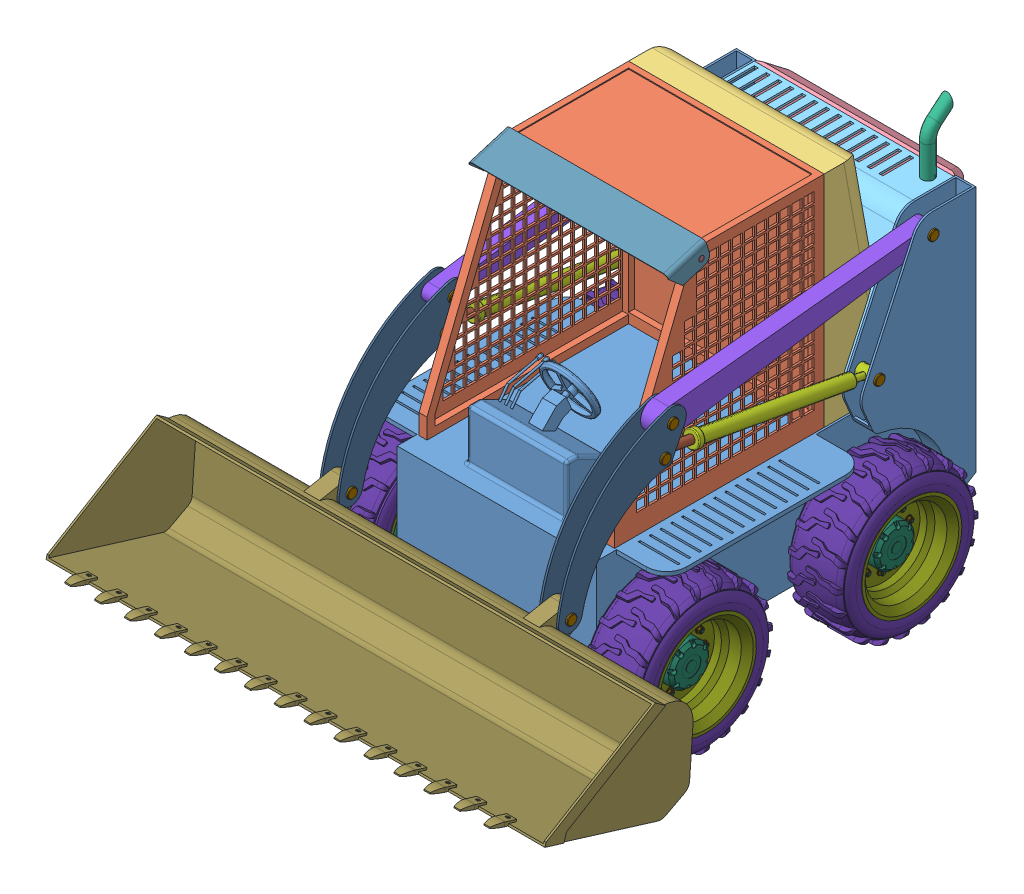
SolidWorks assembly Main Assembly, configuration Default. Lengths in mm.
Overall size (2500 2109.45 3011.96).
86 component instances, 18 part files, 55 mates.
Components (placement in the parent):
- 1. Main Body-1: 1. Main Body [Default] at origin size (1500 1375 1800)
- 2. Cabin-1: 2. Cabin [Default] at (0 600 240) size (980 1100 1050)
- 11. Back Support-1: 11. Back Support [Default] at (0 1150 -285) x (0 0 -1) z (1 0 0) size (350 1100 980)
- 4. Back cover with light-1: 4. Back cover with light [Default] at (0 987.5 -1025) size (1000 775 130)
- 10. Back Cover-1: 10. Back Cover [Default] at (0 1375 -925) x (0 0 -1) z (1 0 0) size (539.33 589.21 1000)
- 12. Exhaust Pipe-1: 12. Exhaust Pipe [Default] at (435 1671.4181 -974.9067) size (60 319.4 125.62)
- 6. Cylinder Body-1: 6. Cylinder Body [Default] at (550 942.7605 442.5974) x (-1 0 0) z (0 0.177626 0.984098) size (85 85 935)
- 9. Lifting Arm 2-1: 9. Lifting Arm 2 [Default] at (550 1275 -719.0464) x (0 0.125982 -0.992033) z (1 0 0) size (1425 140 80)
- 13. Arm pin-1: 13. Arm pin [Default] at (610 1275 -719.0464) x (1 0 0) z (0 -0.292261 0.956339) size (120 50 50)
- 13. Arm pin-2: 13. Arm pin [Default] at (610 782.0093 -448.0114) size (120 50 50)
- 8. Lifting arm 1-1: 8. Lifting arm 1 [Default] at (595 1109.3336 585.4763) x (0 0.085474 -0.99634) z (1 0 0) size (690 680 10)
- 7.Cylinder Rod-1: 7.Cylinder Rod [Default] at (550 975.5356 624.1817) x (0 -0.177626 -0.984098) z (1 0 0) size (950 60 80)
- 8. Lifting arm 1-2: 8. Lifting arm 1 [Default] at (505 1109.3336 585.4763) x (0 0.085474 -0.99634) z (1 0 0) size (690 680 10)
- 13. Arm pin-4: 13. Arm pin [Default] at (490 975.5356 624.1817) x (-1 0 0) z (0 0.679336 -0.733827) size (120 50 50)
- 13. Arm pin-5: 13. Arm pin [Default] at (610 1109.3336 585.4763) x (1 0 0) z (0 -0.694207 -0.719775) size (120 50 50)
- 9. Lifting Arm 2-2: 9. Lifting Arm 2 [Default] at (-550 1105.5541 615.2373) x (0 -0.125982 0.992033) z (-1 0 0) size (1425 140 80)
- 13. Arm pin-6: 13. Arm pin [Default] at (-610 1109.3336 585.4763) x (-1 0 0) z (0 0.694207 0.719775) size (120 50 50)
- 13. Arm pin-7: 13. Arm pin [Default] at (-490 975.5356 624.1817) x (1 0 0) z (0 -0.679336 0.733827) size (120 50 50)
- 8. Lifting arm 1-3: 8. Lifting arm 1 [Default] at (-595 1109.3336 585.4763) x (0 0.085474 -0.99634) z (1 0 0) size (690 680 10)
- 8. Lifting arm 1-4: 8. Lifting arm 1 [Default] at (-505 1109.3336 585.4763) x (0 0.085474 -0.99634) z (1 0 0) size (690 680 10)
- 7.Cylinder Rod-2: 7.Cylinder Rod [Default] at (-550 975.5356 624.1817) x (0 -0.177626 -0.984098) z (1 0 0) size (950 60 80)
- 6. Cylinder Body-2: 6. Cylinder Body [Default] at (-550 942.7605 442.5974) x (1 0 0) z (0 0.177626 0.984098) size (85 85 935)
- 13. Arm pin-8: 13. Arm pin [Default] at (-610 1275 -719.0464) x (-1 0 0) z (0 0.292261 -0.956339) size (120 50 50)
- 13. Arm pin-9: 13. Arm pin [Default] at (-610 782.0093 -448.0114) x (-1 0 0) z (0 0 -1) size (120 50 50)
- 3. Bucket-1: 3. Bucket [Default] at (0 149.3103 1587.7184) x (1 0 0) z (0 0.293221 0.956045) size (2500 554.94 810.74)
- 13. Arm pin-10: 13. Arm pin [Default] at (-490 513.4808 1096.4161) x (1 0 0) z (0 -0.694207 -0.719775) size (120 50 50)
- 13. Arm pin-11: 13. Arm pin [Default] at (610 513.4808 1096.4161) x (1 0 0) z (0 -0.688251 -0.725473) size (120 50 50)
- 14. Cabin pin-1: 14. Cabin pin [Default] at (-484 1650 340) x (-1 0 0) z (0 -0.924225 -0.381849) size (20 26 26)
- 5. Cabin Cap-1: 5. Cabin Cap [Default] at (0 1594.3596 385.871) x (1 0 0) z (0 -0.289151 0.957284) size (1000 100 200)
- 14. Cabin pin-2: 14. Cabin pin [Default] at (484 1650 340) size (20 26 26)
- Tire Sub Assembly-1: Tire Sub Assembly [Default] at (194.4921 299.2826 729.3509) x (1 0 0) z (0 -0.820784 -0.571238) size (367.75 833.89 833.89)
  - 15. Axle-1: 15. Axle [Default] at (370.5079 7.8342 176.4257) size (290 300 300)
  - 16. Rim-1: 16. Rim [Default] at (475.5079 7.8342 176.4257) size (300 500 500)
  - 17. Tire-1: 17. Tire [Default] at (475.5079 7.8342 176.4257) x (1 0 0) z (0 0.148505 0.988912) size (305.49 733.15 733.15)
  - hex flange nut_am-1: hex flange nut_am [B18.2.2.4M - Hex flange nut, M16 x 2 --N] at (496.5079 113.0064 100.0136) x (0 0 -1) z (1 0 0) size (34.5 34.5 16)
  - hex flange nut_am-2: hex flange nut_am [B18.2.2.4M - Hex flange nut, M16 x 2 --N] at (496.5079 137.8342 176.4257) x (0 0 -1) z (1 0 0) size (34.5 34.5 16)
  - hex flange nut_am-3: hex flange nut_am [B18.2.2.4M - Hex flange nut, M16 x 2 --N] at (496.5079 113.0064 252.8378) x (0 0 -1) z (1 0 0) size (34.5 34.5 16)
  - hex flange nut_am-4: hex flange nut_am [B18.2.2.4M - Hex flange nut, M16 x 2 --N] at (496.5079 48.0064 300.063) x (0 0 -1) z (1 0 0) size (34.5 34.5 16)
  - hex flange nut_am-5: hex flange nut_am [B18.2.2.4M - Hex flange nut, M16 x 2 --N] at (496.5079 -32.338 300.063) x (0 0 -1) z (1 0 0) size (34.5 34.5 16)
  - hex flange nut_am-6: hex flange nut_am [B18.2.2.4M - Hex flange nut, M16 x 2 --N] at (496.5079 -97.338 252.8378) x (0 0 -1) z (1 0 0) size (34.5 34.5 16)
  - hex flange nut_am-7: hex flange nut_am [B18.2.2.4M - Hex flange nut, M16 x 2 --N] at (496.5079 -122.1658 176.4257) x (0 0 -1) z (1 0 0) size (34.5 34.5 16)
  - hex flange nut_am-8: hex flange nut_am [B18.2.2.4M - Hex flange nut, M16 x 2 --N] at (496.5079 -97.338 100.0136) x (0 0 -1) z (1 0 0) size (34.5 34.5 16)
  - hex flange nut_am-9: hex flange nut_am [B18.2.2.4M - Hex flange nut, M16 x 2 --N] at (496.5079 -32.338 52.7883) x (0 0 -1) z (1 0 0) size (34.5 34.5 16)
  - hex flange nut_am-10: hex flange nut_am [B18.2.2.4M - Hex flange nut, M16 x 2 --N] at (496.5079 48.0064 52.7883) x (0 0 -1) z (1 0 0) size (34.5 34.5 16)
- Tire Sub Assembly-2: Tire Sub Assembly [Default] at (194.4921 123.7634 -569.6397) x (1 0 0) z (0 0.10455 0.99452) size (367.75 833.89 833.89)
  - 15. Axle-1: 15. Axle [Default] at (370.5079 7.8342 176.4257) size (290 300 300)
  - 16. Rim-1: 16. Rim [Default] at (475.5079 7.8342 176.4257) size (300 500 500)
  - 17. Tire-1: 17. Tire [Default] at (475.5079 7.8342 176.4257) x (1 0 0) z (0 0.148505 0.988912) size (305.49 733.15 733.15)
  - hex flange nut_am-1: hex flange nut_am [B18.2.2.4M - Hex flange nut, M16 x 2 --N] at (496.5079 113.0064 100.0136) x (0 0 -1) z (1 0 0) size (34.5 34.5 16)
  - hex flange nut_am-2: hex flange nut_am [B18.2.2.4M - Hex flange nut, M16 x 2 --N] at (496.5079 137.8342 176.4257) x (0 0 -1) z (1 0 0) size (34.5 34.5 16)
  - hex flange nut_am-3: hex flange nut_am [B18.2.2.4M - Hex flange nut, M16 x 2 --N] at (496.5079 113.0064 252.8378) x (0 0 -1) z (1 0 0) size (34.5 34.5 16)
  - hex flange nut_am-4: hex flange nut_am [B18.2.2.4M - Hex flange nut, M16 x 2 --N] at (496.5079 48.0064 300.063) x (0 0 -1) z (1 0 0) size (34.5 34.5 16)
  - hex flange nut_am-5: hex flange nut_am [B18.2.2.4M - Hex flange nut, M16 x 2 --N] at (496.5079 -32.338 300.063) x (0 0 -1) z (1 0 0) size (34.5 34.5 16)
  - hex flange nut_am-6: hex flange nut_am [B18.2.2.4M - Hex flange nut, M16 x 2 --N] at (496.5079 -97.338 252.8378) x (0 0 -1) z (1 0 0) size (34.5 34.5 16)
  - hex flange nut_am-7: hex flange nut_am [B18.2.2.4M - Hex flange nut, M16 x 2 --N] at (496.5079 -122.1658 176.4257) x (0 0 -1) z (1 0 0) size (34.5 34.5 16)
  - hex flange nut_am-8: hex flange nut_am [B18.2.2.4M - Hex flange nut, M16 x 2 --N] at (496.5079 -97.338 100.0136) x (0 0 -1) z (1 0 0) size (34.5 34.5 16)
  - hex flange nut_am-9: hex flange nut_am [B18.2.2.4M - Hex flange nut, M16 x 2 --N] at (496.5079 -32.338 52.7883) x (0 0 -1) z (1 0 0) size (34.5 34.5 16)
  - hex flange nut_am-10: hex flange nut_am [B18.2.2.4M - Hex flange nut, M16 x 2 --N] at (496.5079 48.0064 52.7883) x (0 0 -1) z (1 0 0) size (34.5 34.5 16)
- Tire Sub Assembly-3: Tire Sub Assembly [Default] at (-194.4921 282.0158 752.2997) x (-1 0 0) z (0 -0.776273 -0.630397) size (367.75 833.89 833.89)
  - 15. Axle-1: 15. Axle [Default] at (370.5079 7.8342 176.4257) size (290 300 300)
  - 16. Rim-1: 16. Rim [Default] at (475.5079 7.8342 176.4257) size (300 500 500)
  - 17. Tire-1: 17. Tire [Default] at (475.5079 7.8342 176.4257) x (1 0 0) z (0 0.148505 0.988912) size (305.49 733.15 733.15)
  - hex flange nut_am-1: hex flange nut_am [B18.2.2.4M - Hex flange nut, M16 x 2 --N] at (496.5079 113.0064 100.0136) x (0 0 -1) z (1 0 0) size (34.5 34.5 16)
  - hex flange nut_am-2: hex flange nut_am [B18.2.2.4M - Hex flange nut, M16 x 2 --N] at (496.5079 137.8342 176.4257) x (0 0 -1) z (1 0 0) size (34.5 34.5 16)
  - hex flange nut_am-3: hex flange nut_am [B18.2.2.4M - Hex flange nut, M16 x 2 --N] at (496.5079 113.0064 252.8378) x (0 0 -1) z (1 0 0) size (34.5 34.5 16)
  - hex flange nut_am-4: hex flange nut_am [B18.2.2.4M - Hex flange nut, M16 x 2 --N] at (496.5079 48.0064 300.063) x (0 0 -1) z (1 0 0) size (34.5 34.5 16)
  - hex flange nut_am-5: hex flange nut_am [B18.2.2.4M - Hex flange nut, M16 x 2 --N] at (496.5079 -32.338 300.063) x (0 0 -1) z (1 0 0) size (34.5 34.5 16)
  - hex flange nut_am-6: hex flange nut_am [B18.2.2.4M - Hex flange nut, M16 x 2 --N] at (496.5079 -97.338 252.8378) x (0 0 -1) z (1 0 0) size (34.5 34.5 16)
  - hex flange nut_am-7: hex flange nut_am [B18.2.2.4M - Hex flange nut, M16 x 2 --N] at (496.5079 -122.1658 176.4257) x (0 0 -1) z (1 0 0) size (34.5 34.5 16)
  - hex flange nut_am-8: hex flange nut_am [B18.2.2.4M - Hex flange nut, M16 x 2 --N] at (496.5079 -97.338 100.0136) x (0 0 -1) z (1 0 0) size (34.5 34.5 16)
  - hex flange nut_am-9: hex flange nut_am [B18.2.2.4M - Hex flange nut, M16 x 2 --N] at (496.5079 -32.338 52.7883) x (0 0 -1) z (1 0 0) size (34.5 34.5 16)
  - hex flange nut_am-10: hex flange nut_am [B18.2.2.4M - Hex flange nut, M16 x 2 --N] at (496.5079 48.0064 52.7883) x (0 0 -1) z (1 0 0) size (34.5 34.5 16)
- Tire Sub Assembly-4: Tire Sub Assembly [Default] at (-194.4921 307.0923 -314.3192) x (-1 0 0) z (0 -0.908931 -0.416946) size (367.75 833.89 833.89)
  - 15. Axle-1: 15. Axle [Default] at (370.5079 7.8342 176.4257) size (290 300 300)
  - 16. Rim-1: 16. Rim [Default] at (475.5079 7.8342 176.4257) size (300 500 500)
  - 17. Tire-1: 17. Tire [Default] at (475.5079 7.8342 176.4257) x (1 0 0) z (0 0.148505 0.988912) size (305.49 733.15 733.15)
  - hex flange nut_am-1: hex flange nut_am [B18.2.2.4M - Hex flange nut, M16 x 2 --N] at (496.5079 113.0064 100.0136) x (0 0 -1) z (1 0 0) size (34.5 34.5 16)
  - hex flange nut_am-2: hex flange nut_am [B18.2.2.4M - Hex flange nut, M16 x 2 --N] at (496.5079 137.8342 176.4257) x (0 0 -1) z (1 0 0) size (34.5 34.5 16)
  - hex flange nut_am-3: hex flange nut_am [B18.2.2.4M - Hex flange nut, M16 x 2 --N] at (496.5079 113.0064 252.8378) x (0 0 -1) z (1 0 0) size (34.5 34.5 16)
  - hex flange nut_am-4: hex flange nut_am [B18.2.2.4M - Hex flange nut, M16 x 2 --N] at (496.5079 48.0064 300.063) x (0 0 -1) z (1 0 0) size (34.5 34.5 16)
  - hex flange nut_am-5: hex flange nut_am [B18.2.2.4M - Hex flange nut, M16 x 2 --N] at (496.5079 -32.338 300.063) x (0 0 -1) z (1 0 0) size (34.5 34.5 16)
  - hex flange nut_am-6: hex flange nut_am [B18.2.2.4M - Hex flange nut, M16 x 2 --N] at (496.5079 -97.338 252.8378) x (0 0 -1) z (1 0 0) size (34.5 34.5 16)
  - hex flange nut_am-7: hex flange nut_am [B18.2.2.4M - Hex flange nut, M16 x 2 --N] at (496.5079 -122.1658 176.4257) x (0 0 -1) z (1 0 0) size (34.5 34.5 16)
  - hex flange nut_am-8: hex flange nut_am [B18.2.2.4M - Hex flange nut, M16 x 2 --N] at (496.5079 -97.338 100.0136) x (0 0 -1) z (1 0 0) size (34.5 34.5 16)
  - hex flange nut_am-9: hex flange nut_am [B18.2.2.4M - Hex flange nut, M16 x 2 --N] at (496.5079 -32.338 52.7883) x (0 0 -1) z (1 0 0) size (34.5 34.5 16)
  - hex flange nut_am-10: hex flange nut_am [B18.2.2.4M - Hex flange nut, M16 x 2 --N] at (496.5079 48.0064 52.7883) x (0 0 -1) z (1 0 0) size (34.5 34.5 16)
Mates (geometry in assembly coordinates):
- Coincident1: coincident anti-aligned: plane of 1. Main Body-1 through (500 600 865) normal (0 1 0); plane of 2. Cabin-1 through (490 600 -285) normal (0 -1 0)
- Coincident3: coincident aligned: plane of 1. Main Body-1 through (500 580 765) normal (0 0 1); plane of 2. Cabin-1 through (490 600 765) normal (0 0 1)
- Width1: width anti-aligned: plane of 1. Main Body-1 through (500 0 0) normal (1 0 0); plane of 2. Cabin-1 through (-500 0 0) normal (-1 0 0); plane of 1. Main Body-1 through (-490 600 240) normal (-1 0 0); plane of 2. Cabin-1 through (490 600 240) normal (1 0 0)
- Coincident4: coincident anti-aligned: plane of 2. Cabin-1 through (490 1700 -285) normal (0 0 -1); plane of 15. Back Support-1 through (490 1700 -285) normal (0 0 1)
- Coincident5: coincident aligned: plane of 2. Cabin-1 through (490 1700 365) normal (0 1 0); plane of 15. Back Support-1 through (490 1700 -485) normal (0 1 0)
- Coincident6: coincident aligned: plane of 2. Cabin-1 through (490 600 240) normal (1 0 0); plane of 15. Back Support-1 through (490 1150 -285) normal (1 0 0)
- Coincident7: coincident aligned: plane of 1. Main Body-1 through (590 140.5963 -925) normal (0 0 1); plane of 4. Back cover with light-1 through (0 987.5 -925) normal (0 0 1)
- Coincident8: coincident aligned: plane of 1. Main Body-1 through (510 1375 -935) normal (0 1 0); plane of 4. Back cover with light-1 through (-500 1375 -925) normal (0 1 0)
- Coincident9: coincident anti-aligned: plane of 1. Main Body-1 through (500 81.3643 -809.3539) normal (-1 0 0); plane of 4. Back cover with light-1 through (500 1375 -925) normal (1 0 0)
- Coincident10: coincident aligned: plane of 1. Main Body-1 through (510 1375 -935) normal (0 1 0); plane of 14. Back Cove-1 through (500 1375 -925) normal (0 1 0)
- Coincident11: coincident anti-aligned: plane of 4. Back cover with light-1 through (0 987.5 -925) normal (0 0 1); plane of 14. Back Cove-1 through (500 1375 -925) normal (0 0 -1)
- Coincident12: coincident anti-aligned: plane of 1. Main Body-1 through (-500 81.3643 -809.3539) normal (1 0 0); plane of 14. Back Cove-1 through (-500 1275 -719.05) normal (-1 0 0)
- Concentric1: concentric anti-aligned: cylinder of 14. Back Cove-1 through (435 785.7865 -860) axis (0 1 0) radius 30; cylinder of 16. Exhaust Pipe-1 through (435 1533.0323 -860) axis (0 -1 0) radius 30
- Coincident13: coincident anti-aligned: plane of 14. Back Cove-1 through (500 1375 -925) normal (0 1 0); plane of 16. Exhaust Pipe-1 through (435 1375 -860) normal (0 -1 0)
- Parallel1: parallel aligned: plane of 1. Main Body-1 through (0 0 0) normal (1 0 0); plane of 16. Exhaust Pipe-1 through (435 1671.4181 -974.9067) normal (1 0 0)
- Concentric2: concentric anti-aligned: cylinder of 1. Main Body-1 through (-600 1275 -719.0464) axis (1 0 0) radius 20; cylinder of 13. Lifting Arm 2-1 through (590 1275 -719.0464) axis (-1 0 0) radius 20
- Coincident15: coincident anti-aligned: plane of 1. Main Body-1 through (510 81.3643 -809.3539) normal (1 0 0); plane of 13. Lifting Arm 2-1 through (510 1109.3336 585.4763) normal (-1 0 0)
- Concentric3: concentric aligned: cylinder of 1. Main Body-1 through (-600 782.0093 -448.0114) axis (1 0 0) radius 15; cylinder of 10. Cylinder Body-1 through (510 782.0093 -448.0114) axis (1 0 0) radius 15
- Coincident16: coincident anti-aligned: plane of 1. Main Body-1 through (510 81.3643 -809.3539) normal (1 0 0); plane of 10. Cylinder Body-1 through (510 782.0093 -448.0114) normal (-1 0 0)
- Concentric4: concentric aligned: cylinder of 1. Main Body-1 through (-600 1275 -719.0464) axis (1 0 0) radius 20; cylinder of 17. Arm pin-1 through (610 1275 -719.0464) axis (1 0 0) radius 15
- Coincident17: coincident anti-aligned: plane of 1. Main Body-1 through (600 81.3643 -809.3539) normal (1 0 0); plane of 17. Arm pin-1 through (600 1289.3451 -714.6625) normal (-1 0 0)
- Concentric5: concentric aligned: cylinder of 1. Main Body-1 through (-600 782.0093 -448.0114) axis (1 0 0) radius 15; cylinder of 17. Arm pin-2 through (610 782.0093 -448.0114) axis (1 0 0) radius 15
- Coincident18: coincident anti-aligned: plane of 1. Main Body-1 through (600 81.3643 -809.3539) normal (1 0 0); plane of 17. Arm pin-2 through (600 797.0093 -448.0114) normal (-1 0 0)
- Concentric7: concentric aligned: cylinder of 13. Lifting Arm 2-1 through (590 1109.3336 585.4763) axis (-1 0 0) radius 25; cylinder of 12. Lifting arm 1-1 through (600 1109.3336 585.4763) axis (-1 0 0) radius 20
- Coincident20: coincident anti-aligned: plane of 13. Lifting Arm 2-1 through (590 1109.3336 585.4763) normal (1 0 0); plane of 12. Lifting arm 1-1 through (590 1109.3336 585.4763) normal (-1 0 0)
- Concentric10: concentric aligned: cylinder of 10. Cylinder Body-1 through (550 798.8838 -354.5221) axis (0 0.177626 0.984098) radius 32.5; cylinder of 11.Cylinder Rod-1 through (550 812.1202 -281.1886) axis (0 0.177626 0.984098) radius 20
- Concentric11: concentric aligned: cylinder of 12. Lifting arm 1-1 through (600 975.5356 624.1817) axis (-1 0 0) radius 15; cylinder of 11.Cylinder Rod-1 through (590 975.5356 624.1817) axis (-1 0 0) radius 15
- Concentric12: concentric aligned: cylinder of 13. Lifting Arm 2-1 through (590 1109.3336 585.4763) axis (-1 0 0) radius 25; cylinder of 12. Lifting arm 1-2 through (510 1109.3336 585.4763) axis (-1 0 0) radius 20
- Concentric13: concentric aligned: cylinder of 11.Cylinder Rod-1 through (590 975.5356 624.1817) axis (-1 0 0) radius 15; cylinder of 12. Lifting arm 1-2 through (510 975.5356 624.1817) axis (-1 0 0) radius 15
- Coincident21: coincident anti-aligned: plane of 13. Lifting Arm 2-1 through (510 1109.3336 585.4763) normal (-1 0 0); plane of 12. Lifting arm 1-2 through (510 1109.3336 585.4763) normal (1 0 0)
- Concentric20: concentric aligned: cylinder of 11.Cylinder Rod-1 through (590 975.5356 624.1817) axis (-1 0 0) radius 15; cylinder of 17. Arm pin-4 through (490 975.5356 624.1817) axis (-1 0 0) radius 15
- Coincident29: coincident anti-aligned: plane of 12. Lifting arm 1-1 through (600 1109.3336 585.4763) normal (1 0 0); plane of 17. Arm pin-4 through (600 993.8813 641.1651) normal (-1 0 0)
- Concentric23: concentric anti-aligned: cylinder of 12. Lifting arm 1-1 through (600 1109.3336 585.4763) axis (-1 0 0) radius 20; cylinder of 17. Arm pin-5 through (610 1109.3336 585.4763) axis (1 0 0) radius 15
- Coincident31: coincident anti-aligned: plane of 12. Lifting arm 1-1 through (600 1109.3336 585.4763) normal (1 0 0); plane of 17. Arm pin-5 through (600 1098.537 595.8895) normal (-1 0 0)
- Concentric24: concentric anti-aligned: cylinder of 12. Lifting arm 1-1 through (600 513.4808 1096.4161) axis (-1 0 0) radius 20; cylinder of 3. Bucket-1 through (510 513.4808 1096.4161) axis (1 0 0) radius 20
- Coincident32: coincident anti-aligned: plane of 12. Lifting arm 1-1 through (590 1109.3336 585.4763) normal (-1 0 0); plane of 3. Bucket-1 through (590 408.1928 1264.685) normal (1 0 0)
- Concentric25: concentric aligned: cylinder of 12. Lifting arm 1-3 through (-590 513.4808 1096.4161) axis (-1 0 0) radius 20; cylinder of 3. Bucket-1 through (-510 513.4808 1096.4161) axis (-1 0 0) radius 20
- Concentric26: concentric anti-aligned: cylinder of 12. Lifting arm 1-1 through (600 513.4808 1096.4161) axis (-1 0 0) radius 20; cylinder of 17. Arm pin-11 through (610 513.4808 1096.4161) axis (1 0 0) radius 15
- Coincident33: coincident anti-aligned: plane of 12. Lifting arm 1-1 through (600 1109.3336 585.4763) normal (1 0 0); plane of 17. Arm pin-11 through (600 502.5987 1106.7399) normal (-1 0 0)
- Concentric27: concentric anti-aligned: cylinder of 12. Lifting arm 1-4 through (-500 513.4808 1096.4161) axis (-1 0 0) radius 20; cylinder of 17. Arm pin-10 through (-490 513.4808 1096.4161) axis (1 0 0) radius 15
- Coincident34: coincident anti-aligned: plane of 12. Lifting arm 1-4 through (-500 1109.3336 585.4763) normal (1 0 0); plane of 17. Arm pin-10 through (-500 502.6842 1106.8292) normal (-1 0 0)
- Coincident35: coincident aligned: cylinder of 2. Cabin-1 through (-490 1650 340) axis (1 0 0) radius 10; circle of 5. Cabin Cap-1
- Width2: width anti-aligned: plane of 2. Cabin-1 through (490 600 240) normal (1 0 0); plane of 5. Cabin Cap-1 through (-490 600 240) normal (-1 0 0); plane of 2. Cabin-1 through (-500 1565.4445 481.5993) normal (-1 0 0); plane of 5. Cabin Cap-1 through (500 1642.0272 504.7314) normal (1 0 0)
- Concentric28: concentric anti-aligned: cylinder of 5. Cabin Cap-1 through (-500 1650 340) axis (1 0 0) radius 10; cylinder of 18. Cabin pin-2 through (484 1650 340) axis (-1 0 0) radius 10
- Coincident36: coincident anti-aligned: plane of 5. Cabin Cap-1 through (500 1642.0272 504.7314) normal (1 0 0); plane of 18. Cabin pin-2 through (500 1660 340) normal (-1 0 0)
- Concentric29: concentric aligned: cylinder of 18. Cabin pin-1 through (-484 1650 340) axis (1 0 0) radius 10; cylinder of 5. Cabin Cap-1 through (-500 1650 340) axis (1 0 0) radius 10
- Coincident37: coincident anti-aligned: plane of 18. Cabin pin-1 through (-500 1653.8185 330.7578) normal (1 0 0); plane of 5. Cabin Cap-1 through (-500 1565.4445 481.5993) normal (-1 0 0)
- Concentric30: concentric anti-aligned: cylinder of 1. Main Body-1 through (500 150 635) axis (-1 0 0) radius 50; cylinder of Tire Sub Assembly-1/19. Axle-1 through (455 150 635) axis (1 0 0) radius 40
- Distance1: distance = 20 mm anti-aligned: plane of 1. Main Body-1 through (500 0 0) normal (1 0 0); plane of Tire Sub Assembly-1/20. Rim-1 through (520 7.1904 840.1961) normal (-1 0 0)
- Concentric31: concentric anti-aligned: cylinder of 1. Main Body-1 through (500 150 -395) axis (-1 0 0) radius 50; cylinder of Tire Sub Assembly-2/19. Axle-1 through (455 150 -395) axis (1 0 0) radius 40
- Distance2: distance = 20 mm anti-aligned: plane of 1. Main Body-1 through (500 0 0) normal (1 0 0); plane of Tire Sub Assembly-2/20. Rim-1 through (520 398.6299 -421.1375) normal (-1 0 0)
- Concentric32: concentric aligned: cylinder of 1. Main Body-1 through (500 150 635) axis (-1 0 0) radius 50; cylinder of Tire Sub Assembly-3/19. Axle-1 through (-455 150 635) axis (-1 0 0) radius 40
- Distance3: distance = 20 mm anti-aligned: plane of 1. Main Body-1 through (-500 0 0) normal (-1 0 0); plane of Tire Sub Assembly-3/20. Rim-1 through (-520 307.5992 440.9318) normal (1 0 0)
- Concentric33: concentric aligned: cylinder of 1. Main Body-1 through (500 150 -395) axis (-1 0 0) radius 50; cylinder of Tire Sub Assembly-4/19. Axle-1 through (-455 150 -395) axis (-1 0 0) radius 40
- Distance4: distance = 20 mm anti-aligned: plane of 1. Main Body-1 through (-500 0 0) normal (-1 0 0); plane of Tire Sub Assembly-4/20. Rim-1 through (-520 254.2366 -622.2328) normal (1 0 0)
